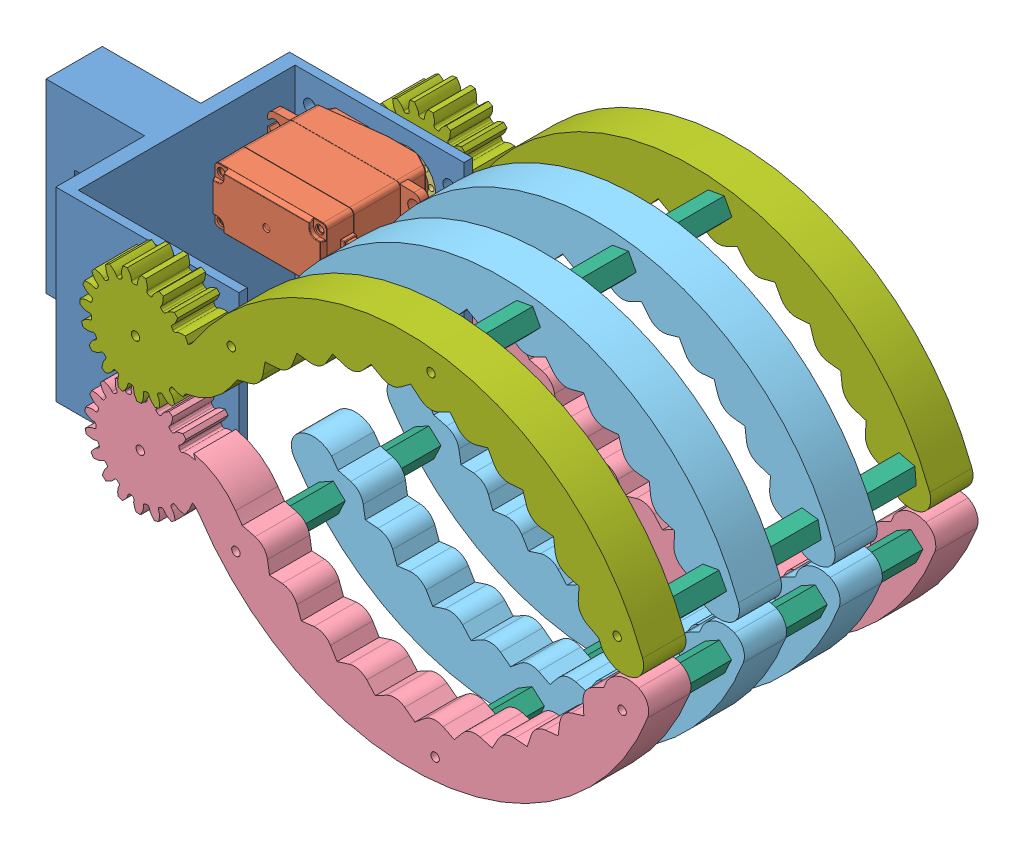
SolidWorks assembly 装配体_爪子加舵机, configuration Default. Lengths in mm.
Overall size (266.2 159.66 118.7).
31 component instances, 7 part files, 9 mates.
Components (placement in the parent):
- 3.固定舵机盘-1: 3.固定舵机盘 [默认] at origin size (100 66 87)
- 4.35KGservo-1: 4.35KGservo [默认] at (35.5165 11.5325 23.201) x (1 0 0) z (0 1 0) size (62.21 45.03 20.04)
- 5.舵机圆形头-1: 5.舵机圆形头 [默认] at (35.5165 11.5325 23.6787) x (1 0 0) z (0 1 0) size (19.5 4.4 19.5)
- 装配体_右爪子-1: 装配体_右爪子 [Default] at (135.3421 -3.8963 -6.499) x (-0.1033 0.99465 0) z (0 0 -1) size (79.93 200.48 117)
  - 1_2.右爪子表面_打印两个-1: 1_2.右爪子表面_打印两个 [Varsayılan] at origin size (79.93 200.48 15)
  - 1_3.爪子中间_打印四个-1: 1_3.爪子中间_打印四个 [Varsayılan] at (-3.0019 8.3684 -34) size (58.35 161.77 15)
  - 2.铜柱连接件-1: 2.铜柱连接件 [Varsayılan] at (-63.8128 8.351 -21.5) size (9.37 9.17 19)
  - 2.铜柱连接件-2: 2.铜柱连接件 [Varsayılan] at (-23.3138 79.3592 -21.5) size (9.37 9.17 19)
  - 2.铜柱连接件-3: 2.铜柱连接件 [Varsayılan] at (-23.3138 79.3592 -55.5) size (9.37 9.17 19)
  - 2.铜柱连接件-4: 2.铜柱连接件 [Varsayılan] at (-28.743 -59.1519 -21.5) size (9.37 9.17 19)
  - 2.铜柱连接件-5: 2.铜柱连接件 [Varsayılan] at (-28.743 -59.1519 -55.5) size (9.37 9.17 19)
  - 2.铜柱连接件-6: 2.铜柱连接件 [Varsayılan] at (-23.3138 79.3592 -89.5) size (9.37 9.17 19)
  - 2.铜柱连接件-7: 2.铜柱连接件 [Varsayılan] at (-28.743 -59.1519 -89.5) size (9.37 9.17 19)
  - 2.铜柱连接件-8: 2.铜柱连接件 [Varsayılan] at (-63.8128 8.351 -55.5) size (9.37 9.17 19)
  - 2.铜柱连接件-9: 2.铜柱连接件 [Varsayılan] at (-63.8128 8.351 -70.5) x (-0.498458 -0.866914 0) z (0 0 -1) size (9.37 9.17 19)
  - 1_3.爪子中间_打印四个-2: 1_3.爪子中间_打印四个 [Varsayılan] at (-3.0019 8.3684 -68) size (58.35 161.77 15)
  - 1_2.右爪子表面_打印两个-2: 1_2.右爪子表面_打印两个 [Varsayılan] at (0 0 -102) size (79.93 200.48 15)
- 装配体_左爪子-1: 装配体_左爪子 [Default] at (135.182 -9.7505 87.201) x (-0.109747 -0.99396 0) z (0 0 1) size (79.66 200.49 117)
  - 1_1.左爪子表面_打印两个-1: 1_1.左爪子表面_打印两个 [Varsayılan] at origin size (79.66 200.49 15)
  - 1_3.爪子中间_打印四个-1: 1_3.爪子中间_打印四个 [Varsayılan] at (-3.003 8.3732 -34) size (58.35 161.77 15)
  - 2.铜柱连接件-1: 2.铜柱连接件 [Varsayılan] at (-28.744 -59.1471 -21.5) x (0.366858 -0.930277 0) z (0 0 1) size (9.37 9.17 19)
  - 2.铜柱连接件-2: 2.铜柱连接件 [Varsayılan] at (-63.8139 8.3557 -21.5) x (0.366858 -0.930277 0) z (0 0 1) size (9.37 9.17 19)
  - 2.铜柱连接件-3: 2.铜柱连接件 [Varsayılan] at (-23.3149 79.364 -21.5) x (0.366858 -0.930277 0) z (0 0 1) size (9.37 9.17 19)
  - 2.铜柱连接件-4: 2.铜柱连接件 [Varsayılan] at (-23.3149 79.364 -55.5) x (-0.923835 -0.38279 0) z (0 0 1) size (9.37 9.17 19)
  - 2.铜柱连接件-5: 2.铜柱连接件 [Varsayılan] at (-63.8139 8.3557 -55.5) x (0.366858 -0.930277 0) z (0 0 1) size (9.37 9.17 19)
  - 2.铜柱连接件-6: 2.铜柱连接件 [Varsayılan] at (-28.744 -59.1471 -55.5) x (0.366858 -0.930277 0) z (0 0 1) size (9.37 9.17 19)
  - 2.铜柱连接件-7: 2.铜柱连接件 [Varsayılan] at (-28.744 -59.1471 -89.5) x (0.366858 -0.930277 0) z (0 0 1) size (9.37 9.17 19)
  - 2.铜柱连接件-8: 2.铜柱连接件 [Varsayılan] at (-23.3149 79.364 -89.5) x (-0.960896 -0.276909 0) z (0 0 1) size (9.37 9.17 19)
  - 2.铜柱连接件-9: 2.铜柱连接件 [Varsayılan] at (-63.8139 8.3557 -89.5) x (0.366858 -0.930277 0) z (0 0 1) size (9.37 9.17 19)
  - 1_3.爪子中间_打印四个-2: 1_3.爪子中间_打印四个 [Varsayılan] at (-3.003 8.3732 -68) size (58.35 161.77 15)
  - 1_1.左爪子表面_打印两个-2: 1_1.左爪子表面_打印两个 [Varsayılan] at (0 0 -102) size (79.66 200.49 15)
Mates (geometry in assembly coordinates):
- 重合1: coincident anti-aligned: plane of 4.35KGservo-1 through (35.5165 11.5325 1.701) normal (0 0 -1); plane of 5.舵机圆形头-1 through (45.5165 11.5325 1.701) normal (0 0 1)
- 同心1: concentric anti-aligned: circle of 4.35KGservo-1; circle of 5.舵机圆形头-1
- 重合4: coincident anti-aligned: plane of 3.固定舵机盘-1 through (5.5165 26.5325 3.001) normal (0 0 1); plane of 4.35KGservo-1 through (35.5165 11.5325 3.001) normal (0 0 -1)
- 同心2: concentric aligned: circle of 3.固定舵机盘-1; circle of 5.舵机圆形头-1
- 重合5: coincident anti-aligned: cylinder of 5.舵机圆形头-1 through (45.5165 11.5325 -0.699) axis (0 0 -1) radius 1.5; circle of 装配体_左爪子-1/1_1.左爪子表面_打印两个-2
- 重合6: coincident anti-aligned: plane of 5.舵机圆形头-1 through (45.5165 11.5325 -2.299) normal (0 0 -1); plane of 装配体_左爪子-1/1_1.左爪子表面_打印两个-2 through (208.7621 8.3998 -2.299) normal (0 0 1)
- 重合10: coincident anti-aligned: plane of 3.固定舵机盘-1 through (45.5165 -24.4675 -3.999) normal (0 0 -1); plane of 装配体_右爪子-1/1_2.右爪子表面_打印两个-1 through (208.7982 -22.5227 -3.999) normal (0 0 1)
- 同心3: concentric aligned: cylinder of 3.固定舵机盘-1 through (45.5165 -24.4675 -96.999) axis (0 0 1) radius 1.5; cylinder of 装配体_右爪子-1/1_2.右爪子表面_打印两个-1 through (45.5165 -24.4675 -18.999) axis (0 0 1) radius 1.5
- 齿轮配合1: gear = 3 : 3 mm: circle of 装配体_右爪子-1/1_2.右爪子表面_打印两个-1; circle of 装配体_左爪子-1/1_1.左爪子表面_打印两个-2
